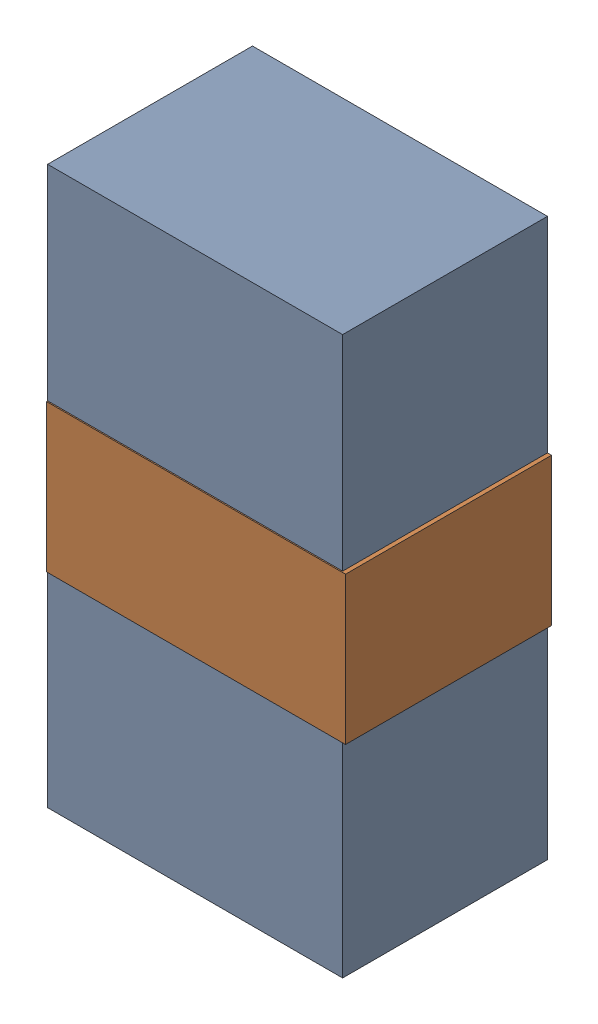
SolidWorks assembly LED2_Motor_1Kanaloa_v2.0.0_Motor, configuration Default. Lengths in mm.
Overall size (1.83 3.4 1.26).
4 component instances, 2 part files, 0 mates.
Components (placement in the parent):
- 334788016-1: 334788016 [Default] at (85.3315 62.738 0) size (1.8 3.4 1.25)
  - Extruded_12-1: Extruded_12 [Default] at origin size (1.8 3.4 1.25)
- 334787760-1: 334787760 [Default] at (85.344 62.738 0) size (1.83 0.9 1.26)
  - Extruded_13-1: Extruded_13 [Default] at origin size (1.83 0.9 1.26)
